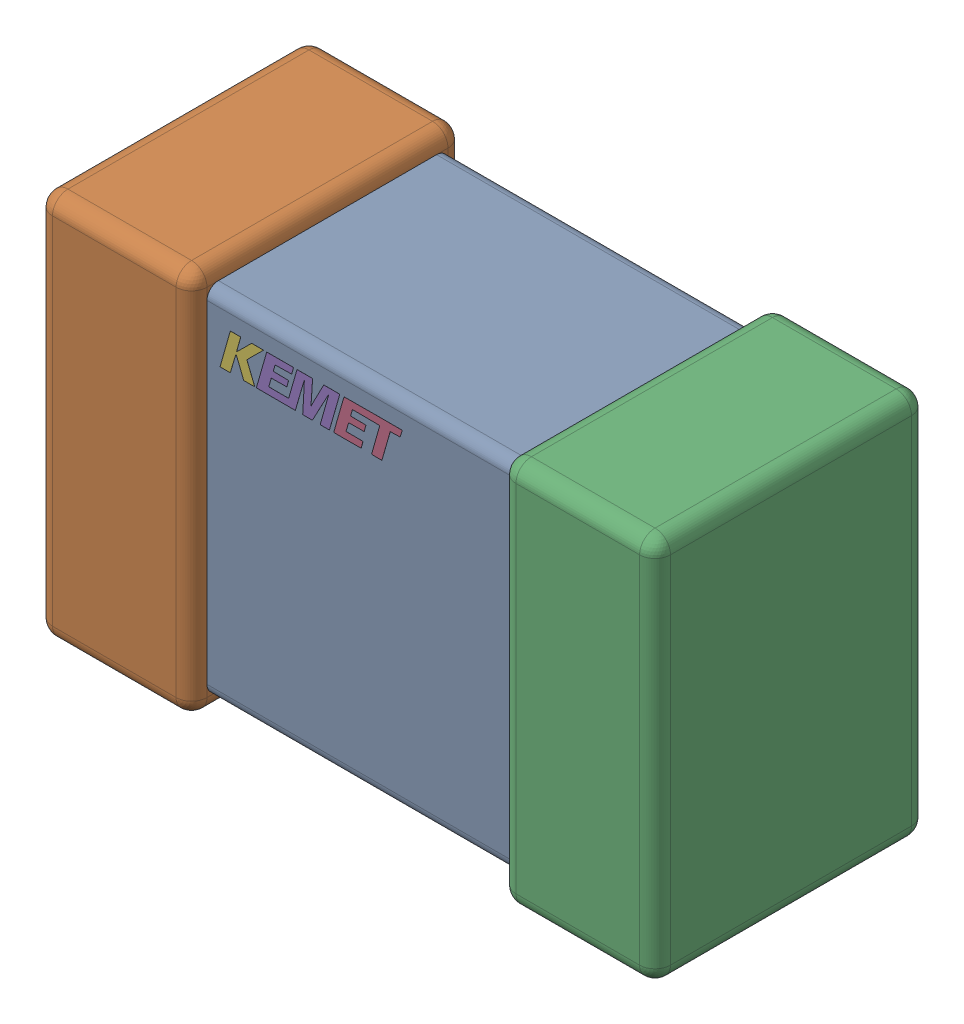
SolidWorks assembly C15.step, configuration Default. Lengths in mm.
Overall size (2 1.25 0.88).
3 component instances, 3 part files, 0 mates.
Components (placement in the parent):
- Cap_KEMET_C0805C472J3HAC_eec.step-1: Cap_KEMET_C0805C472J3HAC_eec.step [Default] at (24.523 53.948 0) size (1 1.15 0.78)
- Cap_KEMET_C0805C472J3HAC_eec-7.step-1: Cap_KEMET_C0805C472J3HAC_eec-7.step [Default] at (24.523 53.948 0) size (2 1.25 0.88)
- Cap_KEMET_C0805C472J3HAC_eec-8.step-1: Cap_KEMET_C0805C472J3HAC_eec-8.step [Default] at (24.523 53.948 0) size (0.59 0.12 0)
